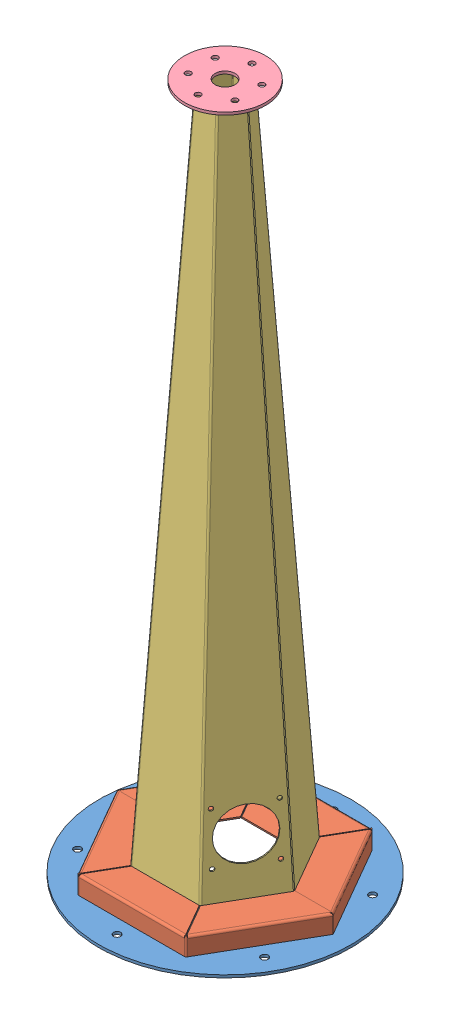
SolidWorks assembly standard-complete, configuration Predeterminado. Lengths in mm.
Overall size (280 766.09 280).
6 component instances, 4 part files, 15 mates.
Components (placement in the parent):
- flangebottom-1: flangebottom [Predeterminado] at origin size (280 3 280)
- base-2: base [Predeterminado] at (0 3 0) size (240.29 20.14 105.17)
- base-3: base [Predeterminado] at (0 3 0) x (-1 0 0) z (0 0 -1) size (240.29 20.14 105.17)
- standard-1: standard [Socket] at (0 23 0) size (153.28 740.12 66.5)
- standard-2: standard [Cable] at (0 23 0) x (-1 0 0) z (0 0 -1) size (153.28 740.12 66.5)
- flange-top-1: flange-top [Predeterminado] at (0 763.091 0) size (90 3 90)
Mates (geometry in assembly coordinates):
- Coincidente5: coincident aligned: plane of base-2 through (0 3 0) normal (0 0 1); plane of assembly through (0 0 0) normal (0 0 1)
- Coincidente6: coincident aligned: plane of base-2 through (0 3 0) normal (1 0 0); plane of assembly through (0 0 0) normal (1 0 0)
- Coincidente7: coincident anti-aligned: plane of base-3 through (0 3 0) normal (0 0 -1); plane of assembly through (0 0 0) normal (0 0 1)
- Coincidente8: coincident anti-aligned: plane of base-3 through (0 3 0) normal (-1 0 0); plane of assembly through (0 0 0) normal (1 0 0)
- Coincidente9: coincident anti-aligned: plane of flangebottom-1 through (0 3 0) normal (0 1 0); plane of base-2 through (-59.4226 3 101.923) normal (0 -1 0)
- Coincidente10: coincident anti-aligned: plane of flangebottom-1 through (0 3 0) normal (0 1 0); plane of base-3 through (59.4226 3 -101.923) normal (0 -1 0)
- Coincidente11: coincident aligned: plane of standard-1 through (0 23 0) normal (0 0 1); plane of assembly through (0 0 0) normal (0 0 1)
- Coincidente12: coincident aligned: plane of standard-1 through (0 23 0) normal (1 0 0); plane of assembly through (0 0 0) normal (1 0 0)
- Coincidente13: coincident anti-aligned: plane of standard-2 through (0 23 0) normal (0 0 -1); plane of assembly through (0 0 0) normal (0 0 1)
- Coincidente14: coincident anti-aligned: plane of standard-2 through (0 23 0) normal (-1 0 0); plane of assembly through (0 0 0) normal (1 0 0)
- Coincidente22: coincident aligned: plane of standard-1 through (0 23 0) normal (0 1 0); plane of assembly through (0 23 0) normal (0 1 0)
- Coincidente23: coincident aligned: plane of standard-2; plane of assembly through (0 23 0) normal (0 1 0)
- Coincidente30: coincident aligned: plane of flange-top-1 through (0 763.091 0) normal (0 1 0); plane of assembly
- Coincidente31: coincident aligned: plane of flange-top-1 through (0 763.091 0) normal (0 0 1); plane of assembly
- Coincidente32: coincident aligned: plane of flange-top-1 through (0 763.091 0) normal (1 0 0); plane of assembly
